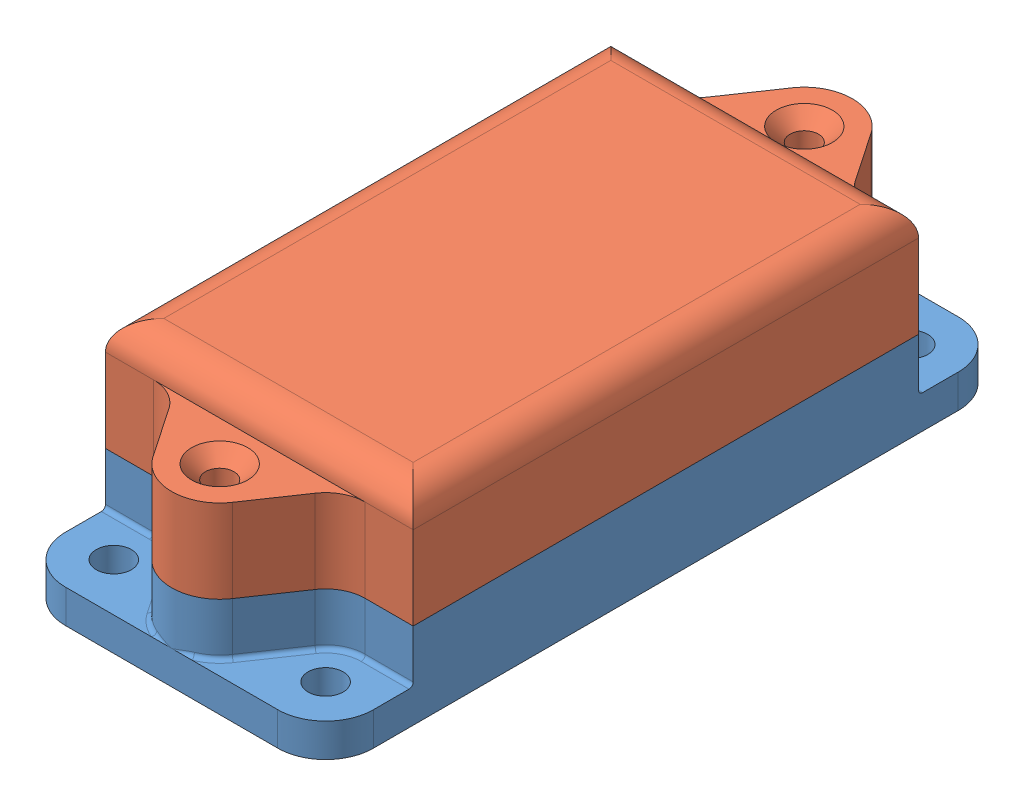
SolidWorks assembly Сборка1, configuration Default. Lengths in mm.
Overall size (36.9 23.8 81.6).
2 component instances, 2 part files, 3 mates.
Components (placement in the parent):
- Низ+уши-1: Низ+уши [По умолчанию] at origin size (36.9 11.8 81.6)
- Крышка-1: Крышка [По умолчанию] at (0 23.8 -57) x (1 0 0) z (0 0 -1) size (36.9 17.7 81.6)
Mates (geometry in assembly coordinates):
- Совпадение1: coincident: plane of assembly; plane of assembly; plane of Низ+уши-1 through (-1.8 1.5 0) normal (-1 0 0); plane of Крышка-1 through (-1.8 22.3 -57) normal (-1 0 0)
- Совпадение2: coincident: plane of assembly; plane of assembly; plane of Низ+уши-1 through (0 10.3 0) normal (0 1 0); plane of Крышка-1 through (0 10.3 -57) normal (0 -1 0)
- Концентричный1: concentric: cylinder of assembly; cylinder of assembly; cylinder of Низ+уши-1 through (16.65 37.7847 6.55) axis (0 -1 0) radius 1.6; cylinder of Крышка-1 through (16.65 20.3 6.55) axis (0 1 0) radius 1.7
